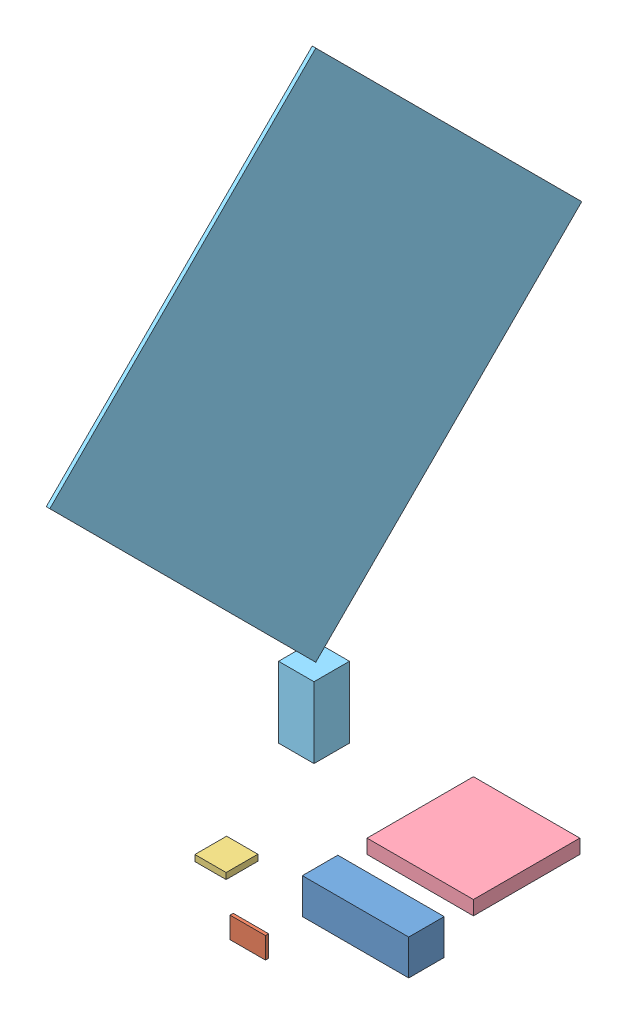
SolidWorks assembly Sattelite, configuration Default. Lengths in mm.
Overall size (932.8 1745.29 1500).
5 component instances, 5 part files, 0 mates.
Components (placement in the parent):
- LNFE-1: LNFE [Default] at origin size (300 100 100)
- DBE Receiver (OEM729)-1: DBE Receiver (OEM729) [Default] at (-91.2064 -82.9277 111.1859) size (100 60 9)
- DBE Processor (Zynq 7020)-1: DBE Processor (Zynq 7020) [Default] at (-198.0083 28.1569 56.8675) size (88.1 17.3 89.5)
- L-Band Antenna-1: L-Band Antenna [Default] at (270.5936 169.8991 -216.9167) size (300 40 300)
- P-I Deployable Antenna-1: P-I Deployable Antenna [Default] at (-439.3634 -66.2281 -404.5926) size (100 1700 1500)
